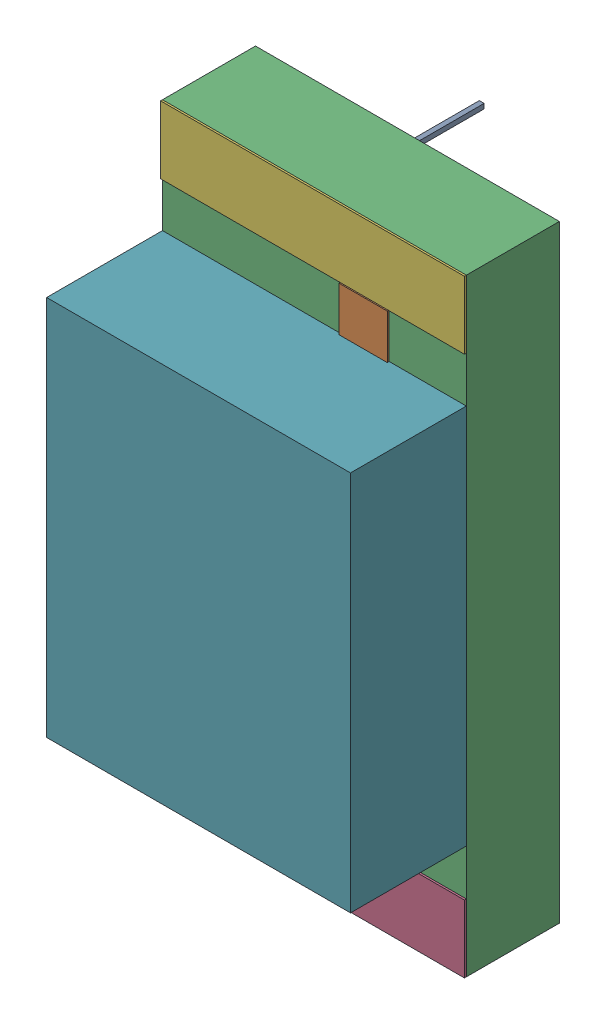
SolidWorks assembly Ddebug1, configuration Défaut. Lengths in mm.
Overall size (1.6 3.2 1.52).
15 component instances, 6 part files, 0 mates.
Components (placement in the parent):
- SW3dPS-LED1206R-1: SW3dPS-LED1206R [Défaut] at (33.5406 30.7341 0) x (0 -1 0) z (0 0 1) size (3.2 1.6 1.52)
  - SW3dPS-LED1206R_Board-1: SW3dPS-LED1206R_Board [Défaut] at (0 0 -0.4039) size (0.03 0.03 0.42)
  - SW3dPS-LED1206R_Open_CASCADE_STEP_translator_6.2_278.2-1: SW3dPS-LED1206R_Open_CASCADE_STEP_translator_6.2_278.2 [Défaut] at origin size (3.2 1.6 1.1)
    - SW3dPS-LED1206R_352699472-1: SW3dPS-LED1206R_352699472 [Défaut] at (0.6096 0.0254 0.5027) size (0.65 0.76 0.01)
      - SW3dPS-LED1206R_Extruded3-1: SW3dPS-LED1206R_Extruded3 [Défaut] at origin size (0.65 0.76 0.01)
    - SW3dPS-LED1206R_352697936-1: SW3dPS-LED1206R_352697936 [Défaut] at (1.524 0.0127 0.0127) size (3.2 1.6 0.49)
      - SW3dPS-LED1206R_Extruded1-1: SW3dPS-LED1206R_Extruded1 [Défaut] at origin size (3.2 1.6 0.49)
    - SW3dPS-LED1206R_352697808-1: SW3dPS-LED1206R_352697808 [Défaut] at (2.9464 0.0127 0.5027) size (0.36 1.6 0.01)
      - SW3dPS-LED1206R_Extruded-1: SW3dPS-LED1206R_Extruded [Défaut] at origin size (0.36 1.6 0.01)
    - SW3dPS-LED1206R_352698192-1: SW3dPS-LED1206R_352698192 [Défaut] at (2.1971 0.0254 0.5027) size (1.14 0.76 0.01)
      - SW3dPS-LED1206R_Extruded4-1: SW3dPS-LED1206R_Extruded4 [Défaut] at origin size (1.14 0.76 0.01)
    - SW3dPS-LED1206R_352697808-2: SW3dPS-LED1206R_352697808 [Défaut] at (0.1016 0.0127 0.5027) size (0.36 1.6 0.01)
      - SW3dPS-LED1206R_Extruded-1: SW3dPS-LED1206R_Extruded [Défaut] at origin size (0.36 1.6 0.01)
    - SW3dPS-LED1206R_352701008-1: SW3dPS-LED1206R_352701008 [Défaut] at (1.524 0.0127 0.5027) size (2.01 1.6 0.61)
      - SW3dPS-LED1206R_Extruded2-1: SW3dPS-LED1206R_Extruded2 [Défaut] at origin size (2.01 1.6 0.61)
